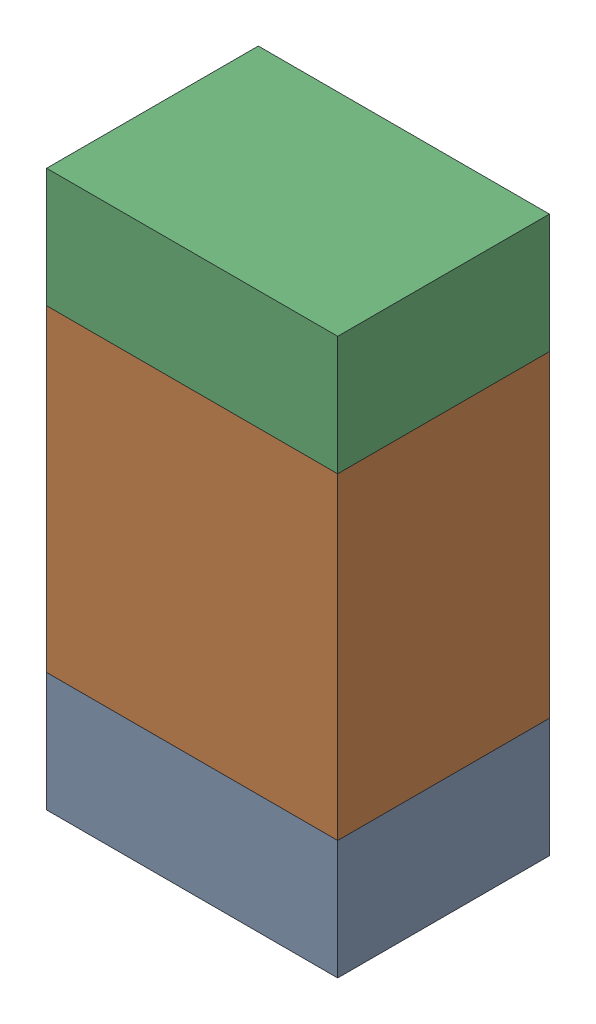
SolidWorks assembly R316_2PCB, configuration Default. Lengths in mm.
Overall size (0.55 1.05 0.4).
6 component instances, 2 part files, 0 mates.
Components (placement in the parent):
- 846483288-1: 846483288 [Default] at (127.9999 92.6874 -2.0638) size (0.55 0.22 0.4)
  - Extruded_12-1: Extruded_12 [Default] at origin size (0.55 0.22 0.4)
- 846483424-1: 846483424 [Default] at (127.9999 93.0999 -2.0638) size (0.55 0.6 0.4)
  - Extruded_13-1: Extruded_13 [Default] at origin size (0.55 0.6 0.4)
- 846483288-2: 846483288 [Default] at (127.9999 93.5124 -2.0638) size (0.55 0.22 0.4)
  - Extruded_12-1: Extruded_12 [Default] at origin size (0.55 0.22 0.4)
